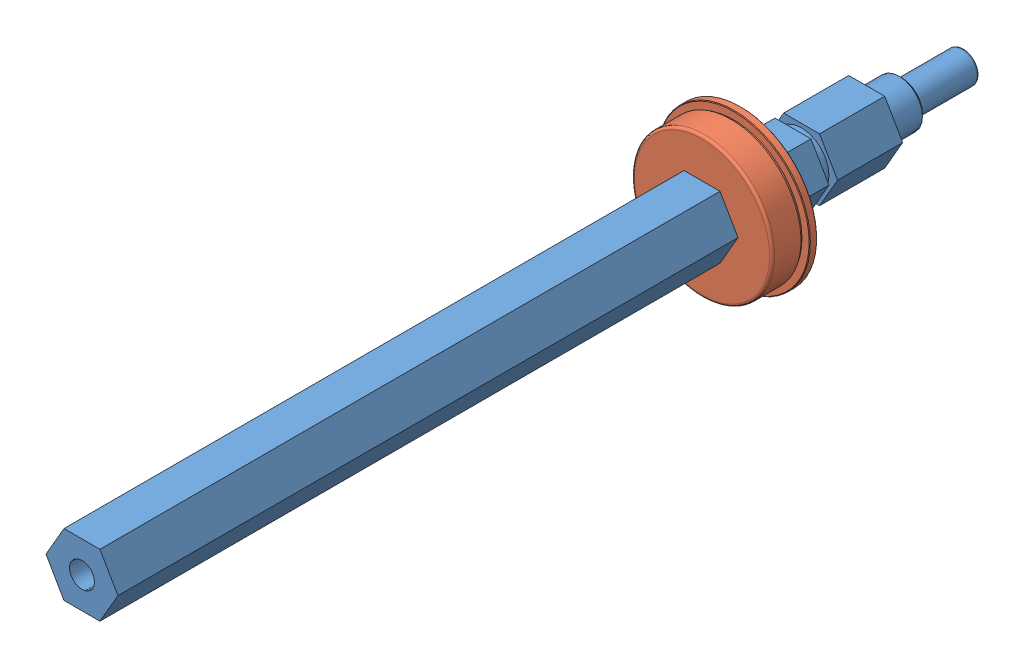
SolidWorks assembly ToughBox mini long 500 hex shaft sub-assy, configuration Default. Lengths in mm.
Overall size (31.12 31.12 179.83).
2 component instances, 2 part files, 0 mates.
Components (placement in the parent):
- am-0801a - Toughbox Long Hex Shaft with Magnet.ipt-1: am-0801a - Toughbox Long Hex Shaft with Magnet.ipt [Default] at (8.4401 -10.8925 79.2944) x (0 0 1) z (-1 0 0) size (179.83 12.7 14.66)
- fr8zz-hex.ipt-1: fr8zz-hex.ipt [Default] at (0 0 6.4033) x (1 0 0) z (0 0 -1) size (31.12 31.12 7.93)
